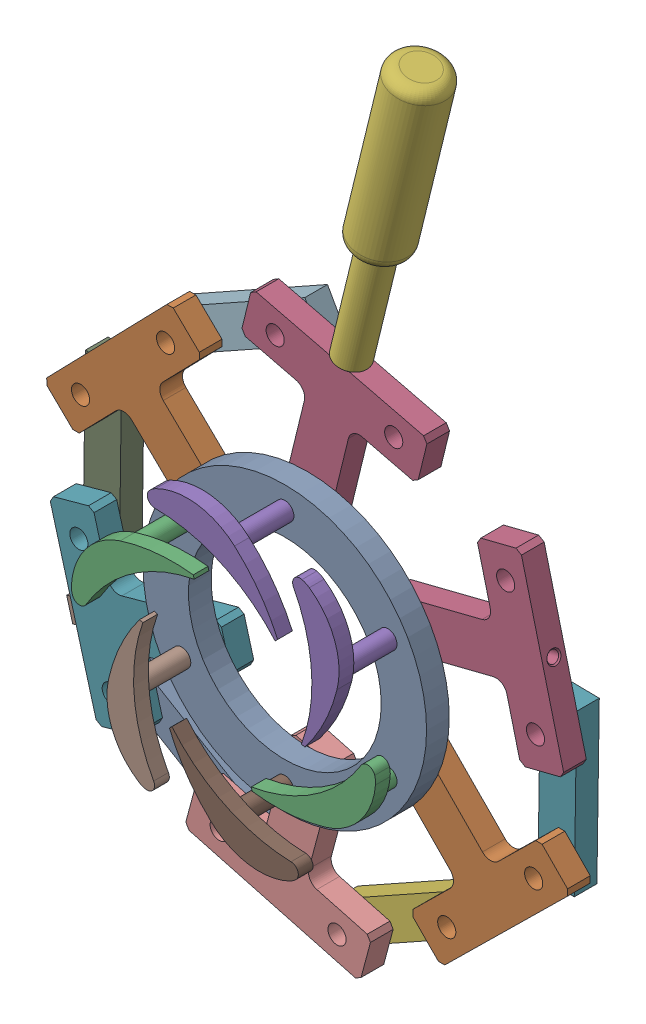
SolidWorks assembly GV000, configuration Default. Lengths in mm.
Overall size (239.22 361.82 61.3).
26 component instances, 6 part files, 21 mates.
Components (placement in the parent):
- GV006-1: GV006 [Default] at origin size (125 125 10)
- GV Sub Assembly-1: GV Sub Assembly [Default] at (-45.4663 26.25 -10) x (0.696813 0.717253 0) z (0 0 1) size (80 78.32 47.3)
  - GV001-1: GV001 [Default] at origin size (80 70 10)
  - GV005-1: GV005 [Default] at (0 0 35.8) size (62.16 25.89 47.3)
- GV Sub Assembly-2: GV Sub Assembly [Default] at (0 52.5 -10) x (0.971369 -0.237574 0) z (0 0 1) size (80 78.32 47.3)
  - GV001-1: GV001 [Default] at origin size (80 70 10)
  - GV005-1: GV005 [Default] at (0 0 35.8) size (62.16 25.89 47.3)
- GV002-1: GV002 [Default] at (26.1331 159.3506 -10) x (0.237574 0.971369 0) z (0.529615 -0.129531 -0.83829) size (142 24 24)
- GV Sub Assembly-3: GV Sub Assembly [Default] at (-45.4663 -26.25 -10) x (-0.265641 0.964072 0) z (0 0 1) size (80 78.32 47.3)
  - GV001-1: GV001 [Default] at origin size (80 70 10)
  - GV005-1: GV005 [Default] at (0 0 35.8) size (62.16 25.89 47.3)
- GV003-3: GV003 [Default] at (-100.4445 14.099 -20) x (0.99991 -0.013401 0) z (0 0 1) size (16 71.4 10)
- GV Sub Assembly-4: GV Sub Assembly [Default] at (0 -52.5 -10) x (-0.965869 0.259032 0) z (0 0 1) size (80 78.32 47.3)
  - GV001-1: GV001 [Default] at origin size (80 70 10)
  - GV005-1: GV005 [Default] at (0 0 35.8) size (62.16 25.89 47.3)
- GV003-4: GV003 [Default] at (-38.4179 93.922 -20) x (0.488709 -0.872447 0) z (0 0 1) size (16 71.4 10)
- GV003-5: GV003 [Default] at (-62.7288 -79.6455 -20) x (0.511911 0.859038 0) z (0 0 1) size (16 71.4 10)
- GV Sub Assembly-5: GV Sub Assembly [Default] at (45.4663 -26.25 -10) x (-0.71233 -0.701845 0) z (0 0 1) size (80 78.32 47.3)
  - GV001-1: GV001 [Default] at origin size (80 70 10)
  - GV005-1: GV005 [Default] at (0 0 35.8) size (62.16 25.89 47.3)
- GV Sub Assembly-8: GV Sub Assembly [Default] at (45.4663 26.25 -10) x (0.244778 -0.969579 0) z (0 0 1) size (80 78.32 47.3)
  - GV001-1: GV001 [Default] at origin size (80 70 10)
  - GV005-1: GV005 [Default] at (0 0 35.8) size (62.16 25.89 47.3)
- GV003-8: GV003 [Default] at (37.2136 -94.2538 -20) x (-0.487641 0.873044 0) z (0 0 1) size (16 71.4 10)
- GV003-9: GV003 [Default] at (100.125 -15.2898 -20) x (0.999893 -0.014613 0) z (0 0 1) size (16 71.4 10)
- GV004-1: GV004 [Default] at (-103.3107 -42.1884 -10) x (-0.265641 0.964072 0) z (-0.964072 -0.265641 0) size (10 24 20.8)
Mates (geometry in assembly coordinates):
- Hinge1: hinge anti-aligned: cylinder of GV Sub Assembly-2/GV001-1 through (0 52.5 -15) axis (0 0 1) radius 4; circle of GV006-1; plane of GV Sub Assembly-2/GV001-1 through (0 52.5 -5) normal (0 0 1); plane of GV006-1 through (0 0 -5) normal (0 0 -1)
- Hinge2: hinge anti-aligned: circle of GV Sub Assembly-1/GV001-1; circle of GV006-1; plane of GV Sub Assembly-1/GV001-1 through (-45.4663 26.25 -5) normal (0 0 1); plane of GV006-1 through (0 0 -5) normal (0 0 -1)
- Concentric1: concentric aligned: line of GV Sub Assembly-2/GV001-1 through (14.2544 110.7822 -10) axis (0.237574 0.971369 0); line of GV002-1 through (11.5223 99.6114 -10) axis (0.237574 0.971369 0)
- Hinge7: hinge anti-aligned: cylinder of GV Sub Assembly-3/GV001-1 through (-45.4663 -26.25 -15) axis (0 0 1) radius 4; cylinder of GV006-1 through (-45.4663 -26.25 -5) axis (0 0 1) radius 4; plane of GV Sub Assembly-3/GV001-1 through (-45.4663 -26.25 -5) normal (0 0 1); plane of GV006-1 through (0 0 -5) normal (0 0 -1)
- Hinge8: hinge anti-aligned: cylinder of GV003-3 through (-100.0732 41.7965 -25) axis (0 0 1) radius 4; cylinder of GV Sub Assembly-1/GV001-1 through (-100.0732 41.7965 -15) axis (0 0 1) radius 4; plane of GV Sub Assembly-1/GV001-1 through (-45.4663 26.25 -15) normal (0 0 -1); plane of GV003-3 through (-100.4445 14.099 -15) normal (0 0 1)
- Hinge9: hinge anti-aligned: cylinder of GV003-3 through (-100.8157 -13.5985 -25) axis (0 0 1) radius 4; cylinder of GV Sub Assembly-3/GV001-1 through (-100.8157 -13.5985 -15) axis (0 0 1) radius 4; plane of GV003-3 through (-100.4445 14.099 -15) normal (0 0 1); plane of GV Sub Assembly-3/GV001-1 through (-45.4663 -26.25 -15) normal (0 0 -1)
- Hinge10: hinge anti-aligned: cylinder of GV003-4 through (-14.2512 107.4592 -25) axis (0 0 1) radius 4; cylinder of GV Sub Assembly-2/GV001-1 through (-14.2512 107.4592 -15) axis (0 0 1) radius 4; plane of GV003-4 through (-38.4179 93.922 -15) normal (0 0 1); plane of GV Sub Assembly-2/GV001-1 through (0 52.5 -15) normal (0 0 -1)
- Hinge12: hinge anti-aligned: cylinder of GV003-4 through (-62.5847 80.3847 -25) axis (0 0 1) radius 4; cylinder of GV Sub Assembly-1/GV001-1 through (-62.5847 80.3847 -15) axis (0 0 1) radius 4; plane of GV003-4 through (-38.4179 93.922 -15) normal (0 0 1); plane of GV Sub Assembly-1/GV001-1 through (-45.4663 26.25 -15) normal (0 0 -1)
- Hinge13: hinge anti-aligned: cylinder of GV Sub Assembly-4/GV001-1 through (0 -52.5 -15) axis (0 0 1) radius 4; cylinder of GV006-1 through (0 -52.5 -5) axis (0 0 1) radius 4; plane of GV Sub Assembly-4/GV001-1 through (0 -52.5 -5) normal (0 0 1); plane of GV006-1 through (0 0 -5) normal (0 0 -1)
- Hinge14: hinge anti-aligned: cylinder of GV003-5 through (-86.5242 -65.4656 -25) axis (0 0 1) radius 4; cylinder of GV Sub Assembly-3/GV001-1 through (-86.5242 -65.4656 -15) axis (0 0 1) radius 4; plane of GV003-5 through (-62.7288 -79.6455 -15) normal (0 0 1); plane of GV Sub Assembly-3/GV001-1 through (-45.4663 -26.25 -15) normal (0 0 -1)
- Hinge15: hinge anti-aligned: cylinder of GV003-5 through (-38.9335 -93.8255 -25) axis (0 0 1) radius 4; cylinder of GV Sub Assembly-4/GV001-1 through (-38.9335 -93.8255 -15) axis (0 0 1) radius 4; plane of GV Sub Assembly-4/GV001-1 through (0 -52.5 -15) normal (0 0 -1); plane of GV003-5 through (-62.7288 -79.6455 -15) normal (0 0 1)
- Hinge17: hinge anti-aligned: cylinder of GV Sub Assembly-5/GV001-1 through (45.4663 -26.25 -15) axis (0 0 1) radius 4; cylinder of GV006-1 through (45.4663 -26.25 -5) axis (0 0 1) radius 4; plane of GV Sub Assembly-5/GV001-1 through (45.4663 -26.25 -5) normal (0 0 1); plane of GV006-1 through (0 0 -5) normal (0 0 -1)
- Hinge18: hinge anti-aligned: cylinder of GV003-8 through (13.0302 -107.7614 -25) axis (0 0 1) radius 4; cylinder of GV Sub Assembly-4/GV001-1 through (13.0302 -107.7614 -15) axis (0 0 1) radius 4; plane of GV003-8 through (37.2136 -94.2538 -15) normal (0 0 1); plane of GV Sub Assembly-4/GV001-1 through (0 -52.5 -15) normal (0 0 -1)
- Hinge19: hinge anti-aligned: cylinder of GV003-8 through (61.3969 -80.7461 -25) axis (0 0 1) radius 4; cylinder of GV Sub Assembly-5/GV001-1 through (61.3969 -80.7461 -15) axis (0 0 1) radius 4; plane of GV Sub Assembly-5/GV001-1 through (45.4663 -26.25 -15) normal (0 0 -1); plane of GV003-8 through (37.2136 -94.2538 -15) normal (0 0 1)
- Hinge20: hinge anti-aligned: cylinder of GV Sub Assembly-8/GV001-1 through (45.4663 26.25 -15) axis (0 0 1) radius 4; cylinder of GV006-1 through (45.4663 26.25 -5) axis (0 0 1) radius 4; plane of GV Sub Assembly-8/GV001-1 through (45.4663 26.25 -5) normal (0 0 1); plane of GV006-1 through (0 0 -5) normal (0 0 -1)
- Hinge21: hinge anti-aligned: cylinder of GV003-9 through (100.5298 12.4072 -25) axis (0 0 1) radius 4; cylinder of GV Sub Assembly-8/GV001-1 through (100.5298 12.4072 -15) axis (0 0 1) radius 4; plane of GV003-9 through (100.125 -15.2898 -15) normal (0 0 1); plane of GV Sub Assembly-8/GV001-1 through (45.4663 26.25 -15) normal (0 0 -1)
- Hinge22: hinge anti-aligned: cylinder of GV003-9 through (99.7203 -42.9869 -25) axis (0 0 1) radius 4; cylinder of GV Sub Assembly-5/GV001-1 through (99.7203 -42.9869 -15) axis (0 0 1) radius 4; plane of GV003-9 through (100.125 -15.2898 -15) normal (0 0 1); plane of GV Sub Assembly-5/GV001-1 through (45.4663 -26.25 -15) normal (0 0 -1)
- Coincident1: coincident anti-aligned: plane of GV Sub Assembly-2/GV001-1 through (-24.6004 120.2851 -5) normal (0.237574 0.971369 0); plane of GV002-1 through (14.2544 110.7822 -10) normal (-0.237574 -0.971369 0)
- Concentric2: concentric aligned: cylinder of GV Sub Assembly-3/GV001-1 through (-103.3107 -42.1884 -10) axis (-0.964072 -0.265641 0) radius 2.5; cylinder of GV004-1 through (-101.7681 -41.7634 -10) axis (-0.964072 -0.265641 0) radius 3.5
- Coincident4: coincident anti-aligned: plane of GV Sub Assembly-3/GV001-1 through (-92.685 -80.7513 -5) normal (-0.964072 -0.265641 0); plane of GV004-1 through (-103.3107 -42.1884 -10) normal (0.964072 0.265641 0)
- Coincident5: coincident anti-aligned: plane of GV Sub Assembly-3/GV001-1 through (-45.4663 -26.25 -15) normal (0 0 -1); plane of GV004-1 through (-103.0963 -36.943 -15) normal (0 0 1)
